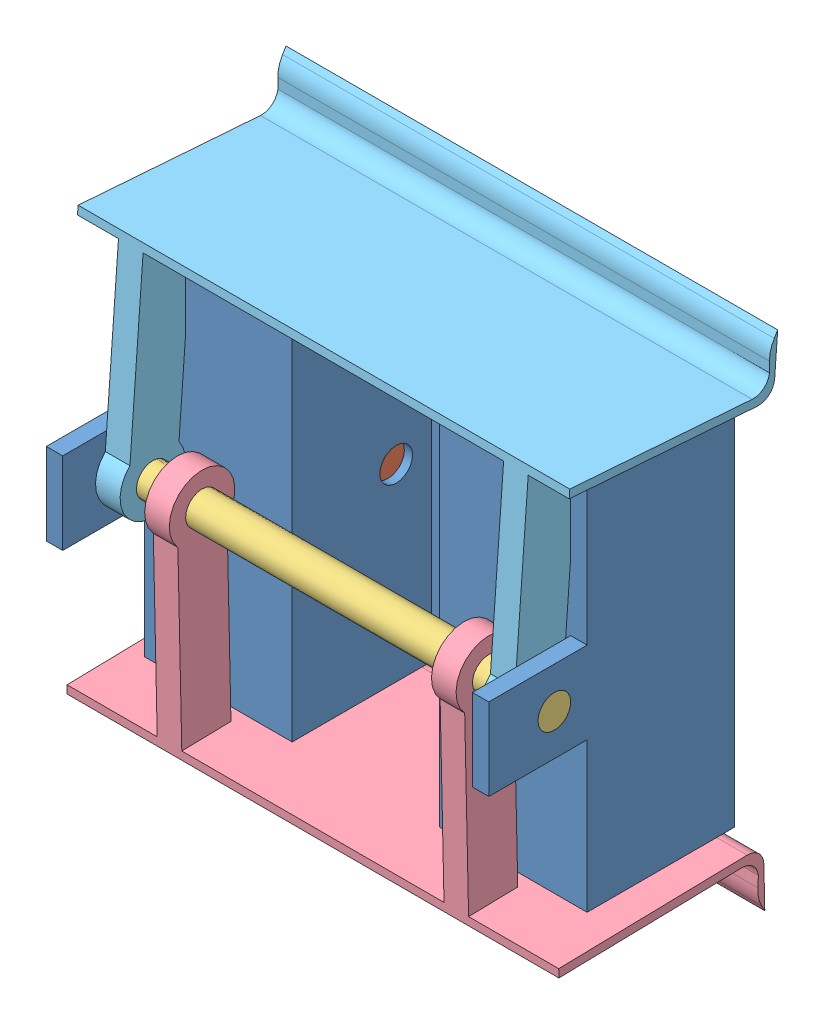
SolidWorks assembly Assemblage1, configuration Défaut. Lengths in mm.
Overall size (300 315.45 169.47).
10 component instances, 5 part files, 18 mates.
Components (placement in the parent):
- CHASSIS INFERIEUR-1: CHASSIS INFERIEUR [Défaut] at (-12.3285 -94.8901 270) size (270 230 150)
- roue70-1: roue70 [Défaut] at (107.6715 -49.8901 296.5) x (0 -0.099718 0.995016) z (-1 0 0) size (70 70 60)
- roue70-2: roue70 [Défaut] at (107.6715 30.1099 296.5) x (0 0 1) z (-1 0 0) size (70 70 60)
- roue70-3: roue70 [Défaut] at (107.6715 110.1099 296.5) x (0 0 1) z (-1 0 0) size (70 70 60)
- roue70-4: roue70 [Défaut] at (-72.3285 30.1099 296.5) x (0 0.394582 0.918861) z (-1 0 0) size (70 70 60)
- roue70-5: roue70 [Défaut] at (-132.3285 -49.8901 296.5) x (0 0 -1) z (1 0 0) size (70 70 60)
- roue70-6: roue70 [Défaut] at (-132.3285 110.1099 296.5) x (0 0 -1) z (1 0 0) size (70 70 60)
- AXE d20-1: AXE d20 [Défaut] at (122.6715 31.3019 380) x (0 0.884269 -0.466977) z (-1 0 0) size (20 20 270)
- JARARA ARRIERE-1: JARARA ARRIERE [Défaut] at (-162.3285 -88.2656 267.3607) x (0 0.999761 0.021849) z (1 0 0) size (177 130 300)
- JARARA AVANT-2: JARARA AVANT [Défaut] at (137.6715 144.8588 261.3036) x (0 -0.997278 0.073736) z (-1 0 0) size (177 130 300)
Mates (geometry in assembly coordinates):
- Coaxiale1: concentric anti-aligned: cylinder of CHASSIS INFERIEUR-1 through (32.6715 30.1099 296.5) axis (1 0 0) radius 10; cylinder of roue70-2 through (107.6715 30.1099 296.5) axis (-1 0 0) radius 5
- Distance1: distance = 10 mm anti-aligned: plane of CHASSIS INFERIEUR-1 through (37.6715 -94.8901 275) normal (1 0 0); plane of roue70-2 through (47.6715 30.1099 296.5) normal (-1 0 0)
- Coaxiale2: concentric anti-aligned: cylinder of CHASSIS INFERIEUR-1 through (32.6715 -49.8901 296.5) axis (1 0 0) radius 5; cylinder of roue70-1 through (107.6715 -49.8901 296.5) axis (-1 0 0) radius 5
- Distance2: distance = 10 mm anti-aligned: plane of CHASSIS INFERIEUR-1 through (37.6715 -94.8901 275) normal (1 0 0); plane of roue70-1 through (47.6715 -49.8901 296.5) normal (-1 0 0)
- Coaxiale3: concentric anti-aligned: cylinder of CHASSIS INFERIEUR-1 through (32.6715 110.1099 296.5) axis (1 0 0) radius 5; cylinder of roue70-3 through (107.6715 110.1099 296.5) axis (-1 0 0) radius 5
- Distance3: distance = 10 mm anti-aligned: plane of CHASSIS INFERIEUR-1 through (37.6715 -94.8901 275) normal (1 0 0); plane of roue70-3 through (47.6715 110.1099 296.5) normal (-1 0 0)
- Coaxiale4: concentric anti-aligned: cylinder of CHASSIS INFERIEUR-1 through (-57.3285 110.1099 296.5) axis (-1 0 0) radius 5; cylinder of roue70-6 through (-132.3285 110.1099 296.5) axis (1 0 0) radius 5
- Distance4: distance = 10 mm anti-aligned: plane of CHASSIS INFERIEUR-1 through (-62.3285 -94.8901 275) normal (-1 0 0); plane of roue70-6 through (-72.3285 110.1099 296.5) normal (1 0 0)
- Coaxiale5: concentric aligned: cylinder of CHASSIS INFERIEUR-1 through (-57.3285 30.1099 296.5) axis (-1 0 0) radius 10; cylinder of roue70-4 through (-72.3285 30.1099 296.5) axis (-1 0 0) radius 5
- Distance5: distance = 10 mm anti-aligned: plane of roue70-4 through (-72.3285 30.1099 296.5) normal (1 0 0); plane of CHASSIS INFERIEUR-1 through (-62.3285 -94.8901 275) normal (-1 0 0)
- Coaxiale6: concentric anti-aligned: cylinder of CHASSIS INFERIEUR-1 through (-57.3285 -49.8901 296.5) axis (-1 0 0) radius 5; cylinder of roue70-5 through (-132.3285 -49.8901 296.5) axis (1 0 0) radius 5
- Distance6: distance = 10 mm anti-aligned: plane of roue70-5 through (-72.3285 -49.8901 296.5) normal (1 0 0); plane of CHASSIS INFERIEUR-1 through (-62.3285 -94.8901 275) normal (-1 0 0)
- Coaxiale7: concentric anti-aligned: cylinder of CHASSIS INFERIEUR-1 through (-137.3285 31.3019 380) axis (-1 0 0) radius 10; cylinder of AXE d20-1 through (-147.3285 31.3019 380) axis (1 0 0) radius 10
- Coïncidente9: coincident aligned: plane of CHASSIS INFERIEUR-1 through (122.6715 -94.8901 270) normal (1 0 0); plane of AXE d20-1 through (122.6715 31.3019 380) normal (1 0 0)
- Coaxiale9: concentric aligned: cylinder of AXE d20-1 through (-147.3285 31.3019 380) axis (1 0 0) radius 10; cylinder of JARARA ARRIERE-1 through (-162.3285 31.3019 380) axis (1 0 0) radius 10
- Coaxiale11: concentric anti-aligned: cylinder of AXE d20-1 through (-147.3285 31.3019 380) axis (1 0 0) radius 10; cylinder of JARARA AVANT-2 through (137.6715 31.3019 380) axis (-1 0 0) radius 10
- Coïncidente12: coincident anti-aligned: plane of CHASSIS INFERIEUR-1 through (112.6715 -94.8901 270) normal (-1 0 0); plane of JARARA AVANT-2 through (112.6715 38.2324 395.0322) normal (1 0 0)
- Distance8: distance = 15 mm anti-aligned: plane of JARARA ARRIERE-1 through (82.6715 23.9758 394.8435) normal (1 0 0); plane of JARARA AVANT-2 through (97.6715 38.2324 395.0322) normal (-1 0 0)
